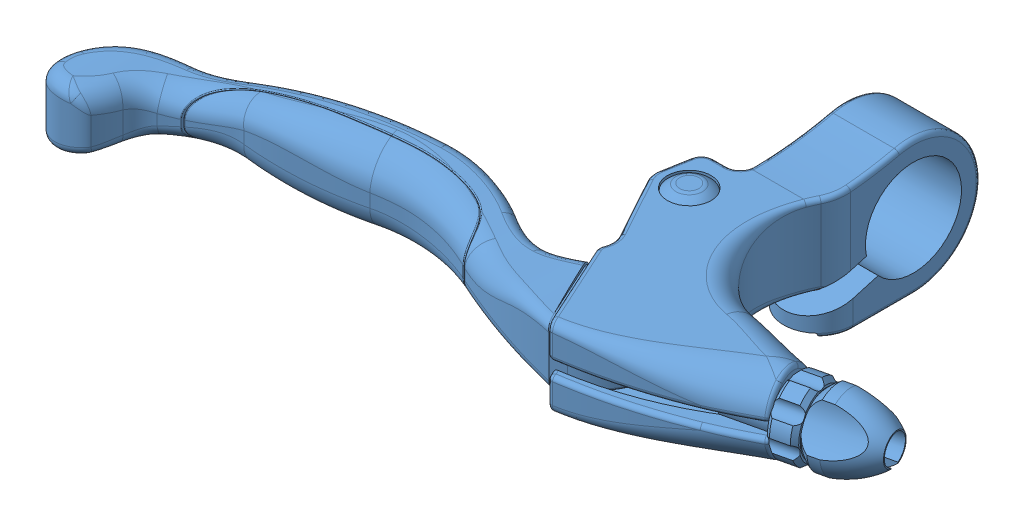
SolidWorks assembly Brake_lever_sport, configuration Default. Lengths in mm.
Overall size (168.25 36.66 100.39).
5 component instances, 3 part files, 8 mates.
Components (placement in the parent):
- Brake_lever_sport-1: Brake_lever_sport [Default] at (-63.1748 -0.8767 29.0328) size (168.25 35.61 100.39)
- socket button head screw_iso-1: socket button head screw_iso [ISO 7380 - M4 x 16 --- 16N] at (-37.7748 -7.5767 26.0867) x (0 1 0) z (0 0 1) size (18.2 7.6 7.6)
- socket button head screw_iso-2: socket button head screw_iso [ISO 7380 - M4 x 16 --- 16N] at (-26.9656 -17.5767 7.6028) x (0 1 0) z (0 0 1) size (18.2 7.6 7.6)
- plain washer 10673 type snl_iso-2: plain washer 10673 type snl_iso [ISO 10673-4.55-S] at (-37.7748 -1.8767 26.0867) x (0 1 0) z (0 0 1) size (1 9 9)
- plain washer 10673 type snl_iso-3: plain washer 10673 type snl_iso [ISO 10673-4.55-S] at (-37.7748 7.6233 26.0867) x (0 -1 0) z (0 0 1) size (1 9 9)
Mates (geometry in assembly coordinates):
- Concentric1: concentric aligned: cylinder of Brake_lever_sport-1 through (-37.7748 17.563 26.0867) axis (0 -1 0) radius 2.1; cylinder of socket button head screw_iso-1 through (-37.7748 -7.5767 26.0867) axis (0 -1 0) radius 3.8
- Coincident1: coincident anti-aligned: plane of Brake_lever_sport-1 through (-37.7748 -5.3767 26.0867) normal (0 -1 0); plane of socket button head screw_iso-1 through (-39.7748 -5.3767 26.0867) normal (0 1 0)
- Concentric2: concentric aligned: cylinder of Brake_lever_sport-1 through (-26.9656 6.6233 7.6028) axis (0 -1 0) radius 2.1; cylinder of socket button head screw_iso-2 through (-26.9656 -17.5767 7.6028) axis (0 -1 0) radius 3.8
- Coincident2: coincident anti-aligned: plane of Brake_lever_sport-1 through (-26.9656 -15.3767 7.1028) normal (0 -1 0); plane of socket button head screw_iso-2 through (-28.9656 -15.3767 7.6028) normal (0 1 0)
- Concentric3: concentric aligned: cylinder of Brake_lever_sport-1 through (-37.7748 17.563 26.0867) axis (0 -1 0) radius 2.1; cylinder of plain washer 10673 type snl_iso-2 through (-37.7748 -0.8767 26.0867) axis (0 -1 0) radius 2.275
- Coincident3: coincident anti-aligned: plane of Brake_lever_sport-1 through (111.1049 -1.8767 30.6945) normal (0 1 0); plane of plain washer 10673 type snl_iso-2 through (-37.7748 -1.8767 26.0867) normal (0 -1 0)
- Concentric4: concentric anti-aligned: cylinder of Brake_lever_sport-1 through (-37.7748 17.563 26.0867) axis (0 -1 0) radius 2.1; cylinder of plain washer 10673 type snl_iso-3 through (-37.7748 6.6233 26.0867) axis (0 1 0) radius 2.275
- Coincident4: coincident anti-aligned: plane of Brake_lever_sport-1 through (111.1049 7.6233 30.6945) normal (0 -1 0); plane of plain washer 10673 type snl_iso-3 through (-37.7748 7.6233 26.0867) normal (0 1 0)
